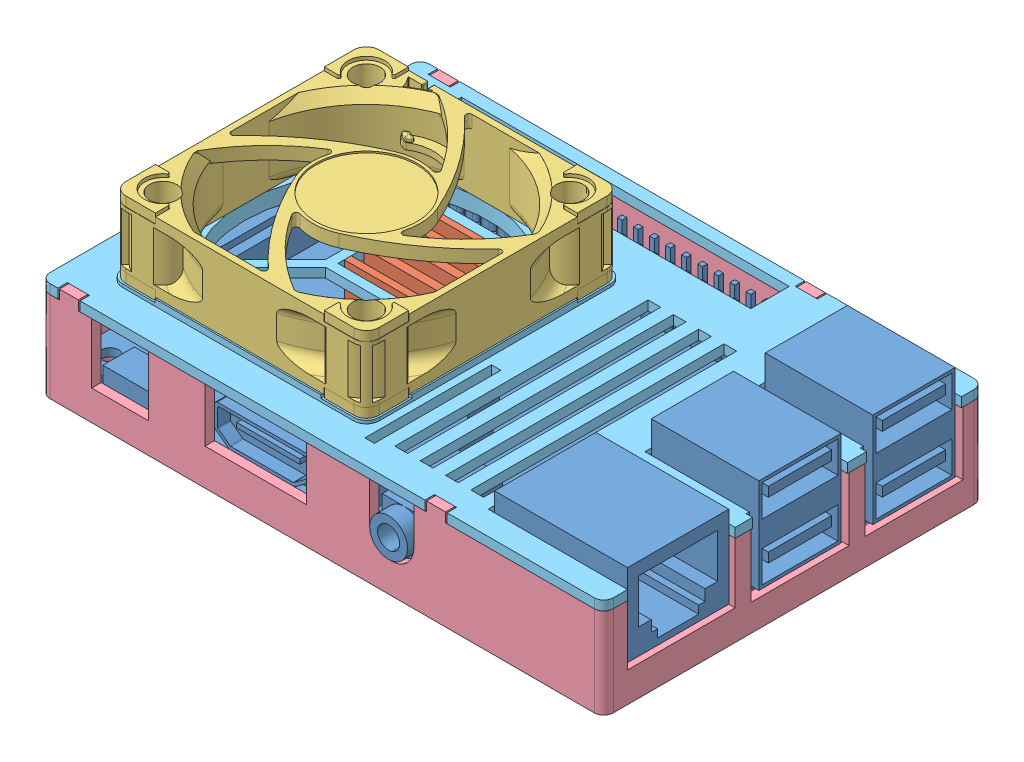
SolidWorks assembly raspberry_pi_case, configuration Default. Lengths in mm.
Overall size (89 28.25 60.5).
5 component instances, 5 part files, 15 mates.
Components (placement in the parent):
- raspberry_pi_3-1: raspberry_pi_3 [Default] at (40.6833 43.3187 63.4712) size (87 17.5 58.5)
- cpu_heatsink-1: cpu_heatsink [Default] at (40.6833 45.5687 63.4712) x (1 0 0) z (0 1 0) size (14 14 10)
- Noctua-NF-A4x10-1: Noctua-NF-A4x10 [Default] at (61.2112 61.5678 43.4991) x (1 0 0) z (0 -1 0) size (40.06 40.06 12.26)
- case_bottom-2: case_bottom [Default] at (40.6833 43.3187 63.4712) x (-1 0 0) z (0 -1 0) size (89 60 15.75)
- case_top-1: case_top [Default] at (40.6833 53.5687 63.4712) x (1 0 0) z (0 1 0) size (89 60 2.5)
Mates (geometry in assembly coordinates):
- InPlace1: in place: plane of raspberry_pi_3-1 through (40.6833 45.5687 63.4712) normal (0 1 0); plane of ? through (0 45.5687 0) normal (0 1 0); moOrthogonalPlaneRef_w of raspberry_pi_3-1 through (40.6833 45.5687 63.4712) normal (0 1 0); plane of ? through (0 45.5687 0) normal (0 0 -1); plane of raspberry_pi_3-1 through (40.6833 45.5687 63.4712) normal (0 1 0); line of ? through (-55 0 45.5687) axis (0 1 0); plane of raspberry_pi_3-1 through (40.6833 45.5687 63.4712) normal (0 1 0); unknown of cpu_heatsink-1
- Coincident1: coincident aligned: plane of raspberry_pi_3-1; plane of cpu_heatsink-1
- Coincident2: coincident aligned: moOrthogonalPlaneRef_w of raspberry_pi_3-1 through (40.6833 45.5687 63.4712) normal (0 0 -1); plane of cpu_heatsink-1 through (40.6833 45.5687 63.4712) normal (0 0 -1)
- Coincident3: coincident anti-aligned: moOrthogonalPlaneRef_w of raspberry_pi_3-1 through (40.6833 45.5687 63.4712) normal (-1 0 0); plane of cpu_heatsink-1
- InPlace2: in place: plane of raspberry_pi_3-1 through (-19.4725 43.3187 41.0985) normal (0 -1 0); plane of ? through (0 43.3187 0) normal (0 -1 0); plane of raspberry_pi_3-1 through (-19.4725 43.3187 41.0985) normal (0 -1 0); unknown of ?; plane of raspberry_pi_3-1 through (-19.4725 43.3187 41.0985) normal (0 -1 0); line of ? through (-55 0 43.3187) axis (0 -1 0); plane of raspberry_pi_3-1 through (40.1833 43.3187 13.9712) normal (0 -1 0); unknown of case_bottom-2
- Coincident4: coincident aligned: plane of raspberry_pi_3-1; plane of case_bottom-2
- Coincident5: coincident aligned: moOrthogonalPlaneRef_w of raspberry_pi_3-1 through (40.6833 43.3187 63.4712) normal (0 0 -1); plane of case_bottom-2
- Coincident6: coincident anti-aligned: moOrthogonalPlaneRef_w of raspberry_pi_3-1 through (40.6833 43.3187 63.4712) normal (1 0 0); plane of case_bottom-2
- InPlace3: in place: plane of case_bottom-2 through (40.6833 51.5687 63.4712) normal (0 1 0); plane of ? through (0 51.5687 0) normal (0 1 0); plane of case_bottom-2 through (40.6833 51.5687 63.4712) normal (0 1 0); plane of ? through (0 51.5687 0) normal (0 0 -1); plane of case_bottom-2 through (40.6833 51.5687 63.4712) normal (0 1 0); line of ? through (-55 0 51.5687) axis (0 1 0); plane of case_bottom-2 through (40.6833 53.5687 63.4712) normal (0 1 0); unknown of case_top-1
- Coincident1: coincident aligned: plane of case_bottom-2; plane of case_top-1
- Coincident2: coincident aligned: moOrthogonalPlaneRef_w of case_bottom-2 through (40.6833 53.5687 63.4712) normal (0 0 -1); plane of case_top-1 through (40.6833 53.5687 63.4712) normal (0 0 -1)
- Coincident3: coincident anti-aligned: moOrthogonalPlaneRef_w of case_bottom-2 through (40.6833 53.5687 63.4712) normal (-1 0 0); plane of case_top-1
- Coincident4: coincident anti-aligned: plane of cpu_heatsink-1 through (40.6833 55.5687 63.4712) normal (0 1 0); plane of Noctua-NF-A4x10-1 through (79.2391 55.5687 61.527) normal (0 -1 0)
- Distance3: distance = 14.5 mm aligned: plane of Noctua-NF-A4x10-1 through (43.1833 56.0687 23.4712) normal (0 0 -1); plane of case_bottom-2 through (35.1833 39.3187 8.9712) normal (0 0 -1)
- Distance4: distance = 6 mm aligned: plane of Noctua-NF-A4x10-1 through (41.1833 56.0687 61.527) normal (-1 0 0); plane of case_bottom-2 through (35.1833 39.3187 68.9712) normal (-1 0 0)
